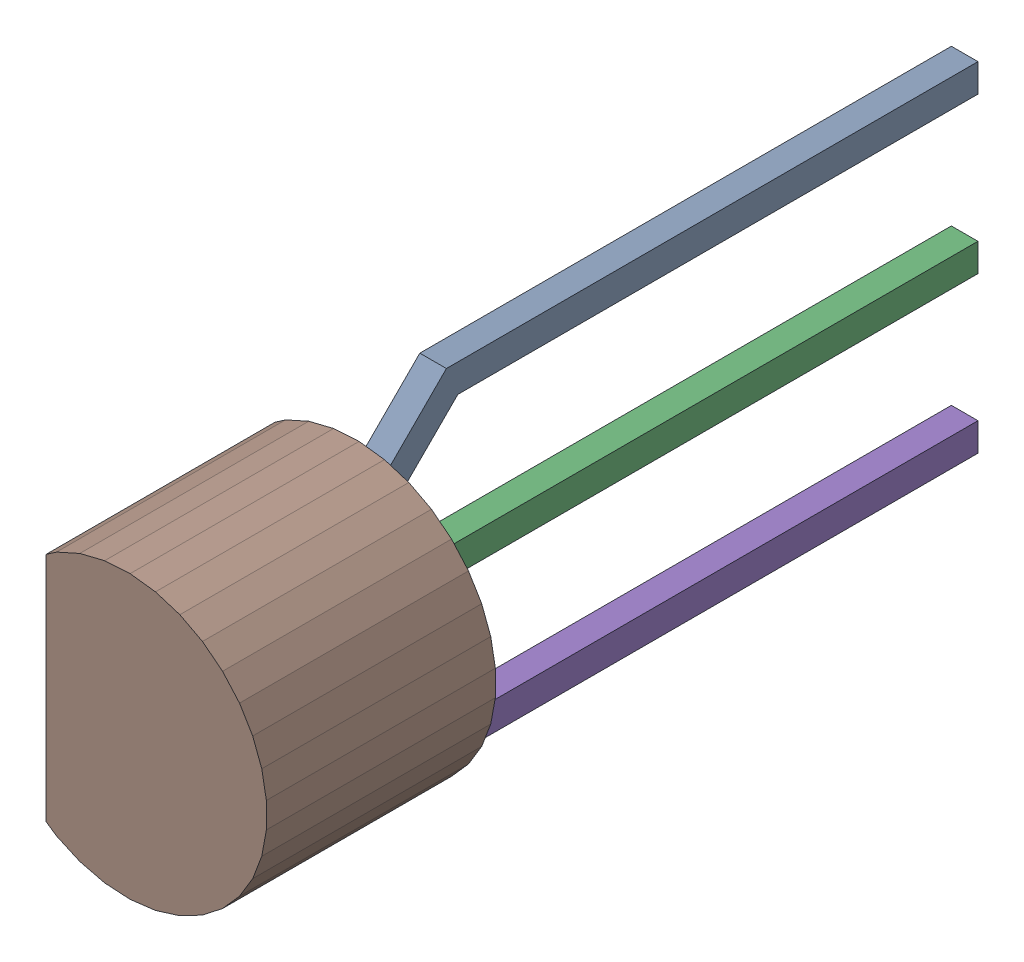
SolidWorks assembly Q3.step, configuration Default. Lengths in mm.
Overall size (3.69 5.68 14.04).
20 component instances, 6 part files, 0 mates.
Components (placement in the parent):
- PCB3.step-1: PCB3.step [Default] at (34.0361 45.8469 4) x (0 -1 0) z (0 0 1) size (5.68 0.46 12.71)
  - Free-Models.step-1: Free-Models.step [Default] at origin size (5.68 0.46 12.71)
    - PCB1.step-1: PCB1.step [Default] at (-1.2706 -0.1276 0) x (1 0 0) z (0 -1 0) size (1.81 12.71 0.46)
      - Free-Models-1.step-1: Free-Models-1.step [Default] at origin size (1.81 12.71 0.46)
        - 523779104.step-1: 523779104.step [Default] at (-0.665 -6.35 -0.35) size (1.81 12.71 0.46)
          - Extruded-43.step-1: Extruded-43.step [Default] at origin size (1.81 12.71 0.46)
      - Board-44.step-1: Board-44.step [Default] at (0 0 -0.2083) size (0.27 0.27 0.21)
    - PCB2.step-1: PCB2.step [Default] at (0.0004 -0.1275 0) x (1 0 0) z (0 -1 0) size (0.47 12.7 0.45)
      - Free-Models-2.step-1: Free-Models-2.step [Default] at origin size (0.47 12.7 0.45)
        - 790454240.step-1: 790454240.step [Default] at (0 -6.35 -0.35) size (0.47 12.7 0.45)
          - Extruded-45.step-1: Extruded-45.step [Default] at origin size (0.47 12.7 0.45)
      - Board-46.step-1: Board-46.step [Default] at (0 0 -0.2083) size (0.27 0.27 0.21)
    - PCB1.step-2: PCB1.step [Default] at (1.2705 0.1276 0) x (-1 0 0) z (0 1 0) size (1.81 12.71 0.46)
      - Free-Models-1.step-1: Free-Models-1.step [Default] at origin size (1.81 12.71 0.46)
        - 523779104.step-1: 523779104.step [Default] at (-0.665 -6.35 -0.35) size (1.81 12.71 0.46)
          - Extruded-43.step-1: Extruded-43.step [Default] at origin size (1.81 12.71 0.46)
      - Board-44.step-1: Board-44.step [Default] at (0 0 -0.2083) size (0.27 0.27 0.21)
  - Board-47.step-1: Board-47.step [Default] at (0 0 -0.2083) size (0.31 0.31 0.21)
- 6100335024.step-1: 6100335024.step [Default] at (34.5437 45.847 1.5) size (3.69 4.72 3.83)
  - Extruded-48.step-1: Extruded-48.step [Default] at origin size (3.69 4.72 3.83)
